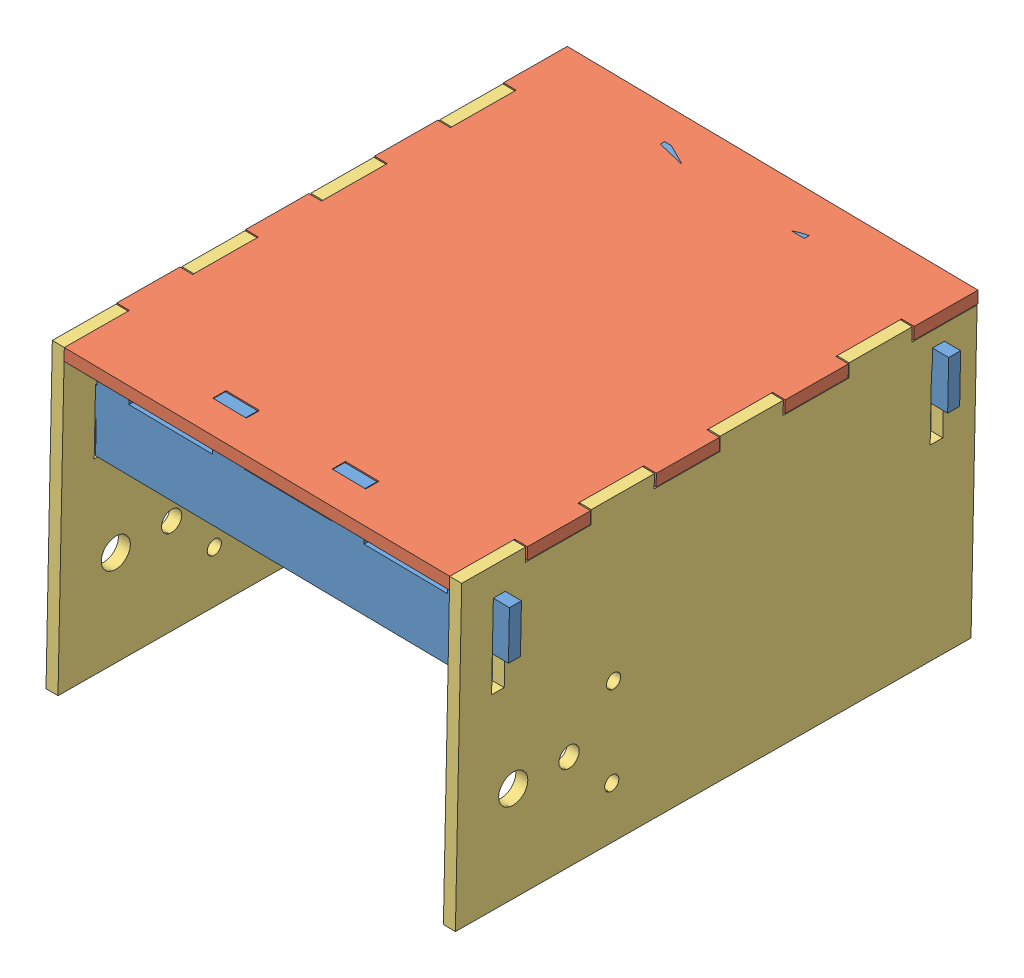
SolidWorks assembly chassis2, configuration Default. Lengths in mm.
Overall size (87.32 61.46 102.01).
5 component instances, 3 part files, 12 mates.
Components (placement in the parent):
- crossbrace-1: crossbrace [Default] at (-22.1734 -18.5625 34.222) x (0.999902 -0.013992 0.000048) z (-0.013992 -0.999878 0.006872) size (87.02 2.36 21.54)
- top_lasercut_2-1: top_lasercut_2 [Default] at (-97.7163 1.7329 42.7986) x (0.999902 -0.013992 0.000048) z (0.000048 0.006872 0.999976) size (80.92 2.36 101.6)
- SidePanel_lasercut_2-1: SidePanel_lasercut_2 [Default] at (-22.4521 -56.6015 43.1959) x (0.999902 -0.013992 0.000048) z (0.000048 0.006872 0.999976) size (2.36 59.64 101.6)
- SidePanel_lasercut_2-2: SidePanel_lasercut_2 [Default] at (-100.7526 -55.5059 43.1921) x (0.999902 -0.013992 0.000048) z (0.000048 0.006872 0.999976) size (2.36 59.64 101.6)
- crossbrace-2: crossbrace [Default] at (-22.1776 -19.1571 -52.3137) x (0.999902 -0.013992 0.000048) z (-0.013992 -0.999878 0.006872) size (87.02 2.36 21.54)
Mates (geometry in assembly coordinates):
- Coincident1: coincident aligned: plane of top_lasercut_2-1 through (-97.6832 4.0948 42.7824) normal (0.013992 0.999878 -0.006872); plane of SidePanel_lasercut_2-2 through (-97.5562 4.093 42.7824) normal (0.013992 0.999878 -0.006872)
- Coincident2: coincident aligned: plane of top_lasercut_2-1 through (-97.6832 4.0948 42.7824) normal (0.013992 0.999878 -0.006872); plane of SidePanel_lasercut_2-1 through (-19.2557 2.9974 42.7861) normal (0.013992 0.999878 -0.006872)
- Coincident3: coincident anti-aligned: plane of top_lasercut_2-1 through (-21.6507 0.6685 42.8023) normal (0.999902 -0.013992 0.000048); plane of SidePanel_lasercut_2-1 through (-22.4521 -56.6015 43.1959) normal (-0.999902 0.013992 -0.000048)
- Coincident4: coincident aligned: plane of top_lasercut_2-1 through (-97.6832 4.0948 42.7824) normal (0.000048 0.006872 0.999976); plane of SidePanel_lasercut_2-1 through (-20.0901 -56.6346 43.196) normal (0.000048 0.006872 0.999976)
- Coincident5: coincident aligned: plane of top_lasercut_2-1 through (-97.6832 4.0948 42.7824) normal (0.000048 0.006872 0.999976); plane of SidePanel_lasercut_2-2 through (-98.3907 -55.5389 43.1922) normal (0.000048 0.006872 0.999976)
- Coincident6: coincident anti-aligned: plane of top_lasercut_2-1 through (-97.5893 1.7311 42.7986) normal (-0.999902 0.013992 -0.000048); plane of SidePanel_lasercut_2-2 through (-98.3907 -55.5389 43.1922) normal (0.999902 -0.013992 0.000048)
- Coincident8: coincident anti-aligned: plane of crossbrace-1 through (-22.1733 -18.5462 36.5842) normal (0.000048 0.006872 0.999976); plane of SidePanel_lasercut_2-1 through (-21.7512 -6.537 36.5016) normal (-0.000048 -0.006872 -0.999976)
- Coincident9: coincident anti-aligned: plane of crossbrace-1 through (-19.2908 0.4649 36.4534) normal (-0.999902 0.013992 -0.000048); plane of SidePanel_lasercut_2-1 through (-20.0901 -56.6346 43.196) normal (0.999902 -0.013992 0.000048)
- Coincident10: coincident anti-aligned: plane of crossbrace-1 through (-97.4358 -5.478 36.498) normal (0.013992 0.999878 -0.006872); plane of SidePanel_lasercut_2-2 through (-100.0518 -5.4414 36.4979) normal (-0.013992 -0.999878 0.006872)
- Coincident11: coincident anti-aligned: plane of SidePanel_lasercut_2-2 through (-100.056 -6.0523 -52.4) normal (0.000048 0.006872 0.999976); plane of crossbrace-2 through (-22.1776 -19.1571 -52.3137) normal (-0.000048 -0.006872 -0.999976)
- Coincident12: coincident anti-aligned: plane of SidePanel_lasercut_2-2 through (-100.7526 -55.5059 43.1921) normal (-0.999902 0.013992 -0.000048); plane of crossbrace-2 through (-99.9575 0.9989 -50.0862) normal (0.999902 -0.013992 0.000048)
- Coincident13: coincident anti-aligned: plane of SidePanel_lasercut_2-2 through (-100.056 -6.0523 -52.4) normal (-0.013992 -0.999878 0.006872); plane of crossbrace-2 through (-97.44 -6.0727 -50.0378) normal (0.013992 0.999878 -0.006872)
